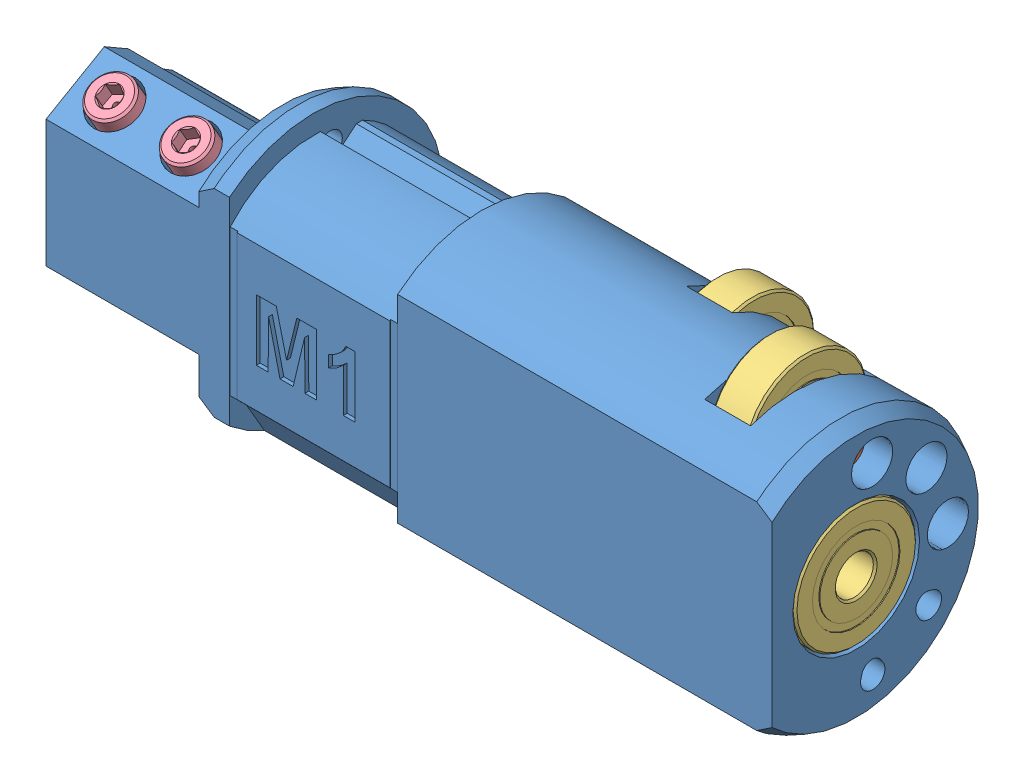
SolidWorks assembly MMU2 Idler Shaft Assembly, configuration Default. Lengths in mm.
Overall size (95 39.64 31.09).
14 component instances, 4 part files, 26 mates.
Components (placement in the parent):
- mmu2-idler(M1)-1: mmu2-idler(M1) [Default] at (7.4542 60.6735 71.2872) size (95 34 28)
- 5x16 Shaft-1: 5x16 Shaft [Default] at (66.4542 72.4912 69.2035) x (0 0 -1) z (1 0 0) size (5 5 16)
- 625 Bearing-1: 625 Bearing [6153K15] at (66.4542 72.4912 69.2035) x (0 0 -1) z (1 0 0) size (16 16 5)
- 625 Bearing-2: 625 Bearing [6153K15] at (52.4542 68.3869 62.0947) x (0 0 -1) z (1 0 0) size (16 16 5)
- 625 Bearing-3: 625 Bearing [6153K15] at (38.4542 60.6735 59.2872) x (0 0 -1) z (1 0 0) size (16 16 5)
- 625 Bearing-4: 625 Bearing [6153K15] at (24.4542 52.96 62.0947) x (0 0 -1) z (1 0 0) size (16 16 5)
- 625 Bearing-5: 625 Bearing [6153K15] at (10.4542 48.8558 69.2035) x (0 0 -1) z (1 0 0) size (16 16 5)
- 625 Bearing-6: 625 Bearing [6153K15] at (74.9542 60.6735 71.2872) x (0 0 -1) z (1 0 0) size (16 16 5)
- 5x16 Shaft-2: 5x16 Shaft [Default] at (52.4542 68.3869 62.0947) x (0 0 -1) z (1 0 0) size (5 5 16)
- 5x16 Shaft-3: 5x16 Shaft [Default] at (38.4542 60.6735 59.2872) x (0 0 -1) z (1 0 0) size (5 5 16)
- 5x16 Shaft-4: 5x16 Shaft [Default] at (24.4542 52.96 62.0947) x (0 0 -1) z (1 0 0) size (5 5 16)
- 5x16 Shaft-5: 5x16 Shaft [Default] at (10.4542 48.8558 69.2035) x (0 0 -1) z (1 0 0) size (5 5 16)
- M3-10 Screw-1: M3-10 Screw [93235A313] at (-12.5458 62.726 72.4723) x (0.999493 -0.015924 0.027582) z (0 -0.866025 -0.5) size (5.5 5.5 13.21)
- M3-10 Screw-2: M3-10 Screw [93235A313] at (-2.5458 62.726 72.4723) x (0.596164 -0.401431 0.6953) z (0 -0.866025 -0.5) size (5.5 5.5 13.21)
Mates (geometry in assembly coordinates):
- Coincident1: coincident aligned: plane of mmu2-idler(M1)-1 through (66.4542 60.6735 71.2872) normal (1 0 0); plane of 625 Bearing-1 through (66.4542 72.4912 69.2035) normal (1 0 0)
- Coincident2: coincident aligned: plane of mmu2-idler(M1)-1 through (52.4542 60.6735 71.2872) normal (1 0 0); plane of 625 Bearing-2 through (52.4542 68.3869 62.0947) normal (1 0 0)
- Coincident3: coincident aligned: plane of mmu2-idler(M1)-1 through (38.4542 60.6735 71.2872) normal (1 0 0); plane of 625 Bearing-3 through (38.4542 60.6735 59.2872) normal (1 0 0)
- Coincident4: coincident aligned: plane of mmu2-idler(M1)-1 through (24.4542 60.6735 71.2872) normal (1 0 0); plane of 625 Bearing-4 through (24.4542 52.96 62.0947) normal (1 0 0)
- Coincident5: coincident aligned: plane of mmu2-idler(M1)-1 through (10.4542 60.6735 71.2872) normal (1 0 0); plane of 625 Bearing-5 through (10.4542 48.8558 69.2035) normal (1 0 0)
- Concentric1: concentric aligned: cylinder of mmu2-idler(M1)-1 through (57.4542 72.4912 69.2035) axis (1 0 0) radius 2.55; cylinder of 625 Bearing-1 through (68.9542 72.4912 69.2035) axis (1 0 0) radius 2.5
- Concentric2: concentric aligned: cylinder of mmu2-idler(M1)-1 through (43.4542 68.3869 62.0947) axis (1 0 0) radius 2.55; cylinder of 625 Bearing-2 through (54.9542 68.3869 62.0947) axis (1 0 0) radius 2.5
- Concentric3: concentric aligned: cylinder of mmu2-idler(M1)-1 through (29.4542 60.6735 59.2872) axis (1 0 0) radius 2.55; cylinder of 625 Bearing-3 through (40.9542 60.6735 59.2872) axis (1 0 0) radius 2.5
- Concentric4: concentric aligned: cylinder of mmu2-idler(M1)-1 through (-26.5458 52.96 62.0947) axis (1 0 0) radius 2.55; cylinder of 625 Bearing-4 through (26.9542 52.96 62.0947) axis (1 0 0) radius 2.5
- Concentric5: concentric aligned: cylinder of mmu2-idler(M1)-1 through (-40.5458 48.8558 69.2035) axis (1 0 0) radius 2.55; cylinder of 625 Bearing-5 through (12.9542 48.8558 69.2035) axis (1 0 0) radius 2.5
- Coincident6: coincident aligned: plane of mmu2-idler(M1)-1 through (66.4542 60.6735 71.2872) normal (1 0 0); plane of 5x16 Shaft-1 through (66.4542 72.4912 69.2035) normal (1 0 0)
- Concentric6: concentric anti-aligned: cylinder of mmu2-idler(M1)-1 through (57.4542 72.4912 69.2035) axis (1 0 0) radius 2.55; cylinder of 5x16 Shaft-1 through (74.4542 72.4912 69.2035) axis (-1 0 0) radius 2.5
- Coincident7: coincident aligned: plane of mmu2-idler(M1)-1 through (52.4542 60.6735 71.2872) normal (1 0 0); plane of 5x16 Shaft-2 through (52.4542 68.3869 62.0947) normal (1 0 0)
- Coincident8: coincident aligned: plane of mmu2-idler(M1)-1 through (38.4542 60.6735 71.2872) normal (1 0 0); plane of 5x16 Shaft-3 through (38.4542 60.6735 59.2872) normal (1 0 0)
- Coincident9: coincident aligned: plane of mmu2-idler(M1)-1 through (24.4542 60.6735 71.2872) normal (1 0 0); plane of 5x16 Shaft-4 through (24.4542 52.96 62.0947) normal (1 0 0)
- Coincident10: coincident aligned: plane of mmu2-idler(M1)-1 through (10.4542 60.6735 71.2872) normal (1 0 0); plane of 5x16 Shaft-5 through (10.4542 48.8558 69.2035) normal (1 0 0)
- Concentric7: concentric anti-aligned: cylinder of mmu2-idler(M1)-1 through (59.4542 68.3869 62.0947) axis (1 0 0) radius 2.7; cylinder of 5x16 Shaft-2 through (60.4542 68.3869 62.0947) axis (-1 0 0) radius 2.5
- Concentric8: concentric anti-aligned: cylinder of mmu2-idler(M1)-1 through (45.4542 60.6735 59.2872) axis (1 0 0) radius 2.7; cylinder of 5x16 Shaft-3 through (46.4542 60.6735 59.2872) axis (-1 0 0) radius 2.5
- Concentric9: concentric anti-aligned: cylinder of mmu2-idler(M1)-1 through (-40.5458 48.8558 69.2035) axis (1 0 0) radius 2.55; cylinder of 5x16 Shaft-5 through (18.4542 48.8558 69.2035) axis (-1 0 0) radius 2.5
- Concentric10: concentric anti-aligned: cylinder of mmu2-idler(M1)-1 through (-43.5458 52.96 62.0947) axis (1 0 0) radius 2.7; cylinder of 5x16 Shaft-4 through (32.4542 52.96 62.0947) axis (-1 0 0) radius 2.5
- Coincident11: coincident: plane of mmu2-idler(M1)-1 through (77.4542 60.6735 71.2872) normal (1 0 0); plane of 625 Bearing-6 through (77.4542 68.4235 71.2872) normal (1 0 0)
- Concentric11: concentric aligned: cylinder of mmu2-idler(M1)-1 through (-18.5458 60.6735 71.2872) axis (1 0 0) radius 2; cylinder of 625 Bearing-6 through (77.4542 60.6735 71.2872) axis (1 0 0) radius 2.5
- Concentric12: concentric anti-aligned: cylinder of mmu2-idler(M1)-1 through (-2.5458 69.6801 76.4872) axis (0 0.866025 0.5) radius 3.1; cylinder of M3-10 Screw-2 through (-2.5458 87.664 86.8702) axis (0 -0.866025 -0.5) radius 2.75
- Concentric13: concentric anti-aligned: cylinder of mmu2-idler(M1)-1 through (-12.5458 69.6801 76.4872) axis (0 0.866025 0.5) radius 3.1; cylinder of M3-10 Screw-1 through (-12.5458 87.664 86.8702) axis (0 -0.866025 -0.5) radius 2.75
- Coincident12: coincident aligned: plane of M3-10 Screw-1 through (-12.5458 87.664 86.8702) normal (0 0.866025 0.5); plane of M3-10 Screw-2 through (-2.5458 87.664 86.8702) normal (0 0.866025 0.5)
- Coincident13: coincident aligned: plane of mmu2-idler(M1)-1 through (-17.5458 60.5235 76.2872) normal (0 -0.866025 -0.5); plane of M3-10 Screw-1 through (-12.5458 62.726 72.4723) normal (0 -0.866025 -0.5)
